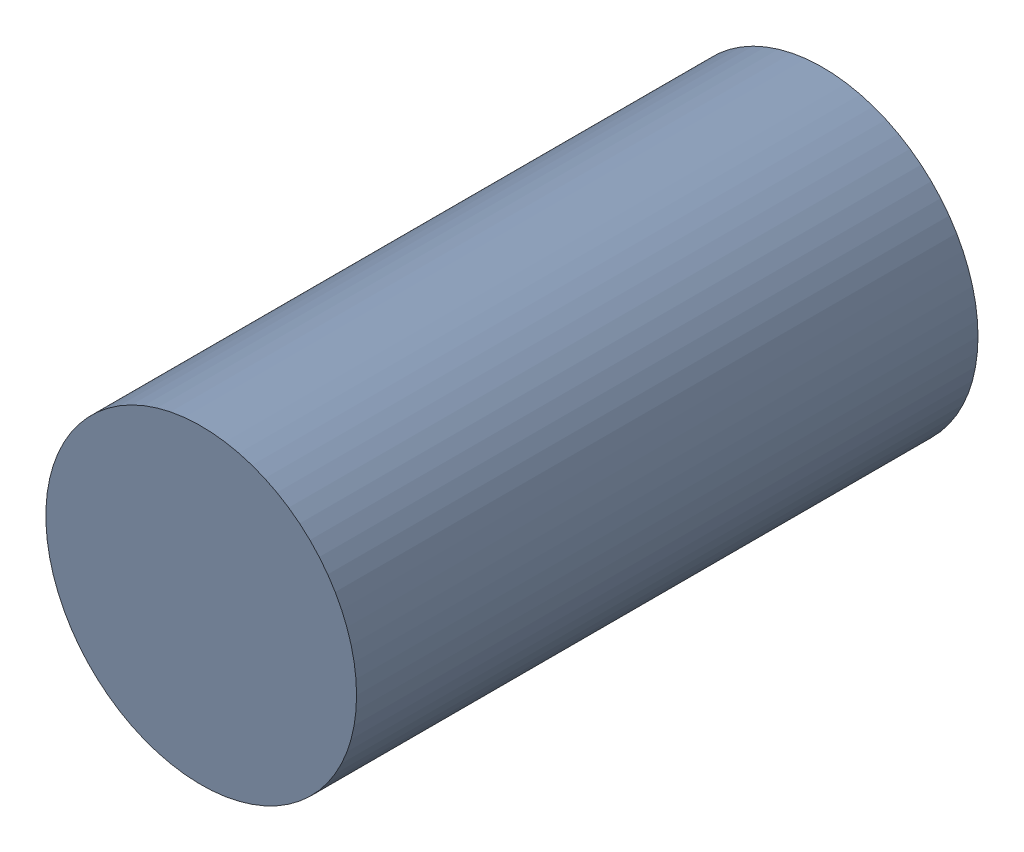
SolidWorks assembly MH9_1.step, configuration Default. Lengths in mm.
Overall size (1 1 2).
2 component instances, 1 part files, 0 mates.
Components (placement in the parent):
- 9228463120_1.step-3: 9228463120_1.step [Default] at (476 317 -1.5) size (1 1 2)
  - Cylinder_1.step-26: Cylinder_1.step [Default] at origin size (1 1 2)
